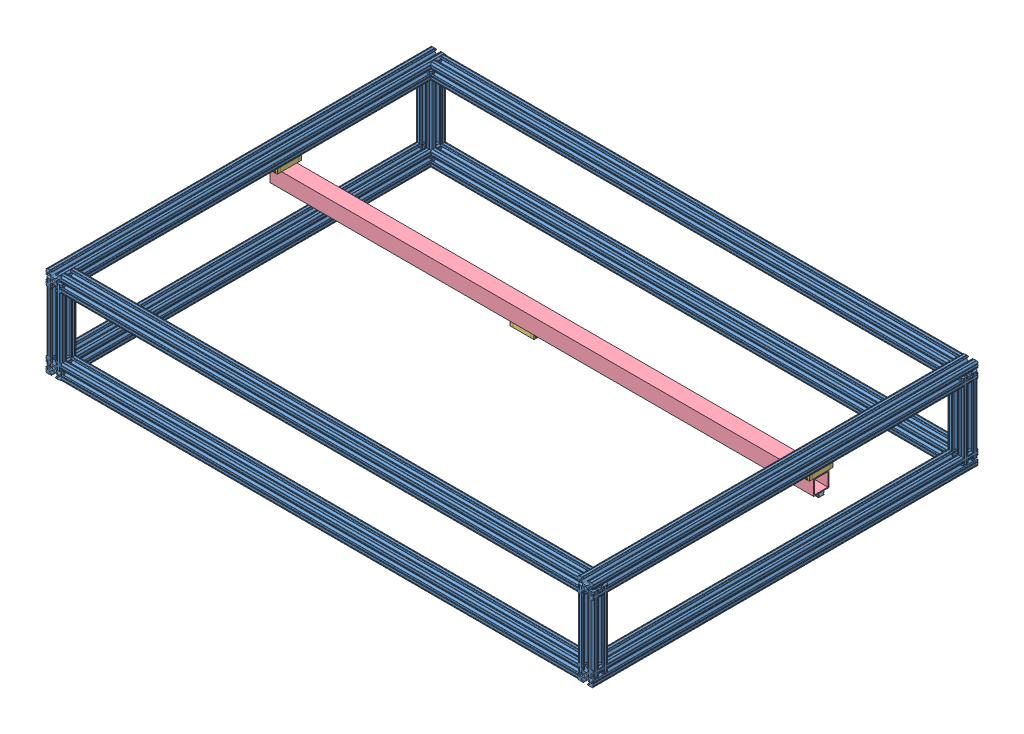
SolidWorks assembly GANTRY M1, configuration Default. Lengths in mm.
Overall size (910.8 150.8 640.8).
8 component instances, 5 part files, 24 mates.
Components (placement in the parent):
- Gantry Frame M1-1: Gantry Frame M1 [Default<As Machined>] at (398.2398 547.7041 619.1858) size (910.8 150.8 640.8)
- MGN-9 Rail - 590mm-1: MGN-9 Rail - 590mm [По умолчанию] at (840.9394 657.4041 324.1858) x (-1 0 0) z (0 0 1) size (9 6 590)
- MGN-9 Rail - 590mm-2: MGN-9 Rail - 590mm [По умолчанию] at (-44.4598 657.4041 324.1858) x (-1 0 0) z (0 0 1) size (9 6 590)
- MGN-9 Carriage-1: MGN-9 Carriage [Default] at (841.0548 654.9041 557.1775) x (1 0 0) z (0 0 -1) size (20 8 41.29)
- MGN-9 Carriage-2: MGN-9 Carriage [Default] at (-44.3444 654.9041 557.1775) x (-1 0 0) z (0 0 1) size (20 8 41.29)
- Crossbar M1-1: Crossbar M1 [Default<As Machined>] at (-54.3444 638.2041 557.1771) size (905.4 25.4 25.4)
- MGN-9 Rail - 905.4mm-1: MGN-9 Rail - 905.4mm [default] at (851.0556 622.5041 557.1774) x (0 0 -1) z (-1 0 0) size (9 6 905.4)
- MGN-9 Carriage-3: MGN-9 Carriage [Default] at (362.8709 620.0041 557.2929) x (0 0 -1) z (-1 0 0) size (20 8 41.29)
Mates (geometry in assembly coordinates):
- Coincident1: coincident anti-aligned: plane of Gantry Frame-1 through (847.2729 660.4041 926.8858) normal (0 -1 0); plane of MGN-9 Rail - 590mm-1 through (845.4394 660.4041 914.1858) normal (0 1 0)
- Parallel1: parallel aligned: line of Gantry Frame-1 through (853.6397 662.5377 939.5858) axis (0 0 -1); line of MGN-9 Rail - 590mm-1 through (845.4394 657.4041 914.1858) axis (0 0 -1)
- Coincident3: coincident anti-aligned: plane of Gantry Frame-1 through (846.2569 673.1041 914.1858) normal (0 0 -1); plane of MGN-9 Rail - 590mm-1 through (845.4394 656.4041 914.1858) normal (0 0 1)
- Distance1: distance = 8.2004 mm aligned: plane of MGN-9 Rail-1 through (845.4394 660.4041 914.1858) normal (1 0 0); plane of Gantry Frame-1 through (853.6398 663.5537 926.8858) normal (1 0 0)
- Coincident5: coincident anti-aligned: plane of Gantry Frame-1 through (-54.0106 660.4041 926.8858) normal (0 -1 0); plane of MGN-9 Rail - 590mm-2 through (-39.9598 660.4041 914.1858) normal (0 1 0)
- Parallel2: parallel aligned: line of Gantry Frame-1 through (-57.16 662.5377 939.5858) axis (0 0 -1); line of MGN-9 Rail - 590mm-2 through (-48.9598 655.4041 914.1858) axis (0 0 -1)
- Coincident7: coincident anti-aligned: plane of Gantry Frame-1 through (-38.1271 673.1041 324.1858) normal (0 0 1); plane of MGN-9 Rail - 590mm-2 through (-39.9598 656.4041 324.1858) normal (0 0 -1)
- Distance2: distance = 8.2004 mm aligned: plane of MGN-9 Rail-2 through (-48.9598 660.4041 914.1858) normal (-1 0 0); plane of Gantry Frame-1 through (-57.1602 666.771 926.8858) normal (-1 0 0)
- Coincident10: coincident anti-aligned: plane of MGN-9 Rail - 590mm-1 through (845.4394 654.4041 914.1858) normal (0 -1 0); plane of MGN-9 Carriage-1 through (841.0548 654.4041 542.2275) normal (0 1 0)
- Parallel3: parallel aligned: plane of Gantry Frame-1 through (853.6398 663.5537 926.8858) normal (1 0 0); plane of MGN-9 Carriage-1 through (851.0548 654.9041 542.2275) normal (1 0 0)
- Coincident12: coincident anti-aligned: plane of MGN-9 Rail - 590mm-1 through (844.1745 656.7561 914.1858) normal (1 0 0); plane of MGN-9 Carriage-1 through (844.1745 656.7022 577.1275) normal (-1 0 0)
- Coincident13: coincident anti-aligned: plane of MGN-9 Rail - 590mm-2 through (-39.9598 654.4041 914.1858) normal (0 -1 0); plane of MGN-9 Carriage-2 through (-44.3444 654.4041 572.1275) normal (0 1 0)
- Parallel4: parallel aligned: plane of Gantry Frame-1 through (-57.1602 666.771 926.8858) normal (-1 0 0); plane of MGN-9 Carriage-2 through (-54.3444 654.9041 572.1275) normal (-1 0 0)
- Coincident15: coincident anti-aligned: plane of MGN-9 Rail - 590mm-2 through (-41.2247 656.7561 914.1858) normal (1 0 0); plane of MGN-9 Carriage-2 through (-41.2247 656.7022 537.2275) normal (-1 0 0)
- Coincident16: coincident anti-aligned: plane of MGN-9 Carriage-2 through (-44.3444 650.9041 572.1275) normal (0 -1 0); plane of Crossbar M1-1 through (851.0556 650.9041 569.8771) normal (0 1 0)
- Coincident17: coincident aligned: plane of MGN-9 Carriage-2 through (-54.3444 654.9041 572.1275) normal (-1 0 0); plane of Crossbar M1-1 through (-54.3444 638.2041 557.1771) normal (-1 0 0)
- Distance3: distance = 7.2504 mm aligned: plane of Crossbar M1-1 through (851.0556 650.9041 569.8771) normal (0 0 1); plane of MGN-9 Carriage-2 through (-48.8444 656.4041 577.1275) normal (0 0 1)
- Distance4: distance = 7.2504 mm aligned: plane of Crossbar M1-1 through (851.0556 650.9041 569.8771) normal (0 0 1); plane of MGN-9 Carriage-1 through (845.5548 656.4041 577.1275) normal (0 0 1)
- Coincident19: coincident anti-aligned: plane of Crossbar M1-1 through (851.0556 625.5041 544.4771) normal (0 -1 0); plane of MGN-9 Rail - 905.4mm-1 through (-54.3444 625.5041 561.6774) normal (0 1 0)
- Parallel5: parallel anti-aligned: line of Crossbar M1-1 through (851.0556 625.5041 544.4771) axis (-1 0 0); line of MGN-9 Rail - 905.4mm-1 through (-54.3444 619.5041 552.6774) axis (1 0 0)
- Coincident21: coincident aligned: plane of MGN-9 Carriage-2 through (-54.3444 654.9041 572.1275) normal (-1 0 0); plane of MGN-9 Rail - 905.4mm-1 through (-54.3444 621.5041 561.6774) normal (-1 0 0)
- Distance5: distance = 8.2004 mm aligned: plane of MGN-9 Rail - 905.4mm-1 through (-54.3444 625.5041 552.6774) normal (0 0 -1); plane of Crossbar M1-1 through (851.0556 625.5041 544.4771) normal (0 0 -1)
- Coincident23: coincident anti-aligned: plane of MGN-9 Rail - 905.4mm-1 through (-54.3444 619.5041 561.6774) normal (0 -1 0); plane of MGN-9 Carriage-3 through (347.9209 619.5041 557.2929) normal (0 1 0)
- Coincident24: coincident anti-aligned: plane of MGN-9 Carriage-3 through (342.9209 621.8022 560.4125) normal (0 0 -1); plane of MGN-9 Rail - 905.4mm-1 through (-54.3444 621.8561 560.4125) normal (0 0 1)
